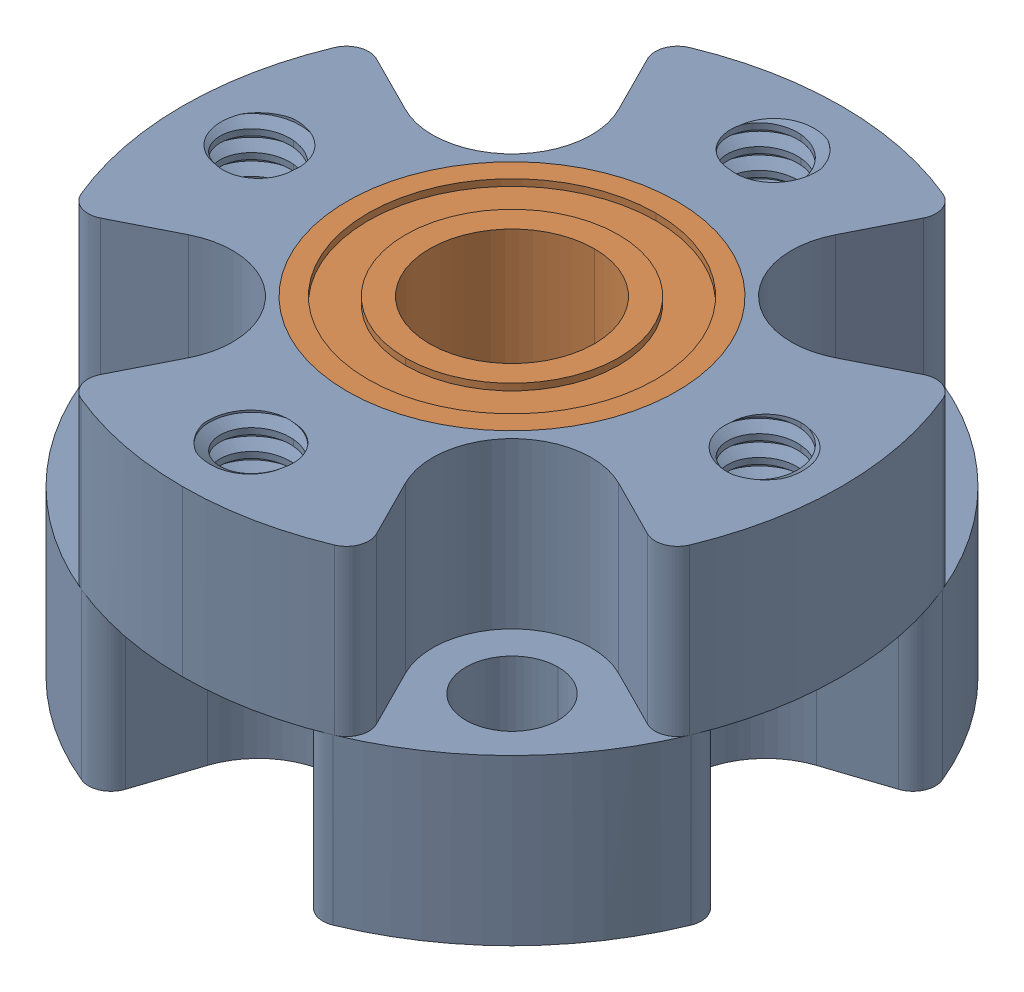
SolidWorks assembly Dual Ball Bearing Hub, configuration Défaut. Lengths in mm.
Overall size (25.4 12.7 25.4).
3 component instances, 2 part files, 0 mates.
Components (placement in the parent):
- Dual Ball Bearing Hub 2-1: Dual Ball Bearing Hub 2 [Défaut] at (-30.0172 -12.6196 20.0992) size (25.4 12.7 25.4)
- Dual Ball Bearing Hub 1-1: Dual Ball Bearing Hub 1 [Défaut] at (-30.0172 -2.3009 20.0992) size (12.7 4.76 12.7)
- Dual Ball Bearing Hub 1-2: Dual Ball Bearing Hub 1 [Défaut] at (-30.0172 -10.2384 20.0992) x (-0.612569 0 0.790417) z (-0.790417 0 -0.612569) size (12.7 4.76 12.7)
